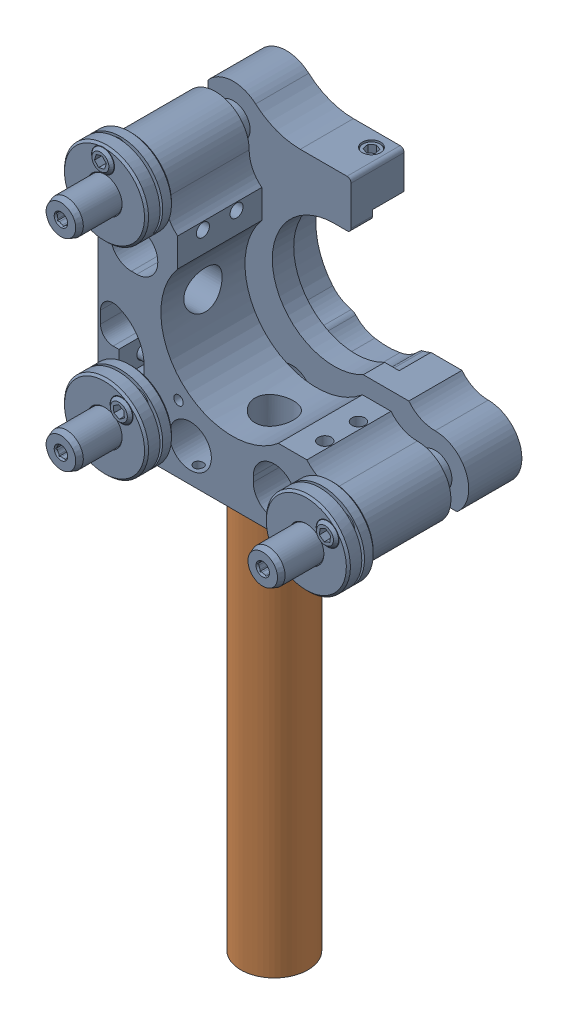
SolidWorks assembly Mirror holder assembled_1, configuration Default. Lengths in mm.
Overall size (53.98 128.56 42.58).
2 component instances, 2 part files, 0 mates.
Components (placement in the parent):
- Newport-U100-A3H.stp_1-1: Newport-U100-A3H.stp_1 [Default] at (-172.1028 -102.6999 -107.2719) size (53.97 53.98 42.58)
- Mirror shaft_1-1: Mirror shaft_1 [Default] at (-78.0363 -104.445 43.1749) x (-0.381849 0 -0.924225) z (0.924225 0 -0.381849) size (12.68 76.17 12.68)
